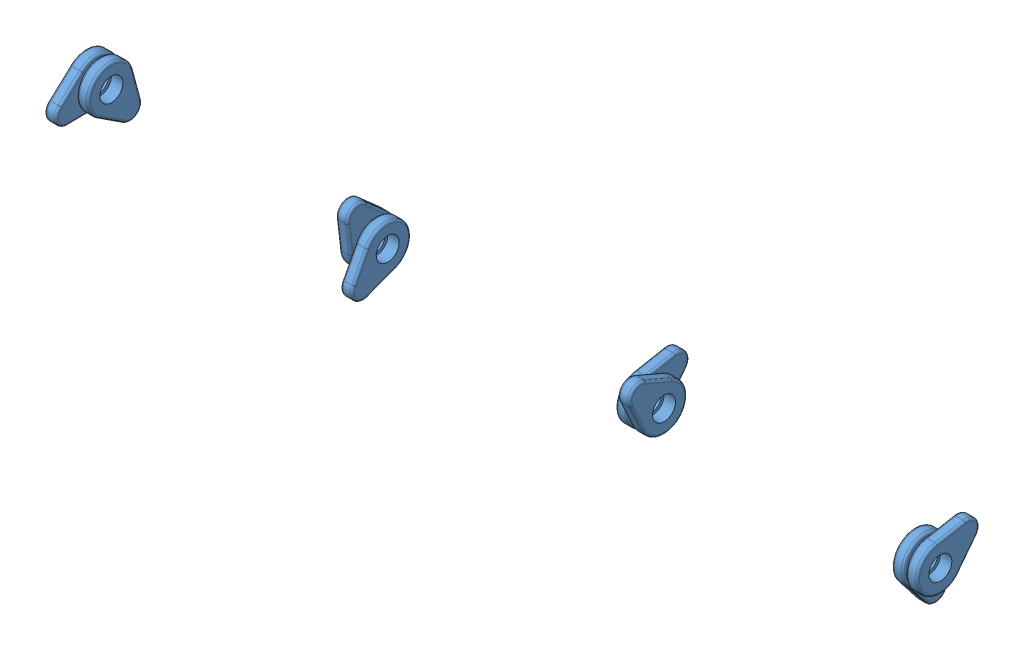
SolidWorks assembly CamRail, configuration Default. Lengths in mm.
Overall size (371 49.3 48.3).
4 component instances, 1 part files, 19 mates.
Components (placement in the parent):
- camX2-1: camX2 [Default] at (-44.0304 461.1901 -302.0136) x (1 0 0) z (0 0.370458 -0.928849) size (11 28.57 29)
- camX2-2: camX2 [Default] at (195.9696 455.2948 -361.5788) x (1 0 0) z (0 -0.52378 0.851854) size (11 28.57 29)
- camX2-7: camX2 [Default] at (75.9696 485.6121 -334.0504) x (1 0 0) z (0 -0.886785 -0.462182) size (11 28.57 29)
- camX2-8: camX2 [Default] at (315.9696 426.6801 -323.7036) x (1 0 0) z (0 0.955327 0.295551) size (11 28.57 29)
Mates (geometry in assembly coordinates):
- Concentric23: concentric aligned: circle of ?; circle of camX2-8
- Concentric24: concentric aligned: circle of ?; circle of camX2-8
- Concentric25: concentric aligned: circle of camX2-1; circle of ?
- Concentric26: concentric aligned: circle of camX2-1; circle of ?
- Concentric27: concentric aligned: circle of ?; circle of camX2-7
- Concentric29: concentric aligned: circle of ?; circle of camX2-7
- Concentric30: concentric aligned: circle of camX2-2; circle of ?
- Concentric31: concentric aligned: circle of camX2-2; circle of ?
- Concentric32: concentric anti-aligned: cylinder of camX2-1 through (-29.2926 455.6781 -331.5424) axis (-1 0 0) radius 5; circle of ?
- Concentric33: concentric aligned: cylinder of camX2-1 through (-29.2926 455.6781 -331.5424) axis (-1 0 0) radius 5; cylinder of ? through (117.7074 455.6781 -331.5424) axis (-1 0 0) radius 5
- Concentric34: concentric anti-aligned: cylinder of camX2-2 through (210.7074 455.6781 -331.5424) axis (-1 0 0) radius 5; circle of ?
- Concentric35: concentric anti-aligned: cylinder of camX2-2 through (210.7074 455.6781 -331.5424) axis (-1 0 0) radius 5; circle of camX2-8
- Distance1: distance = 95 mm anti-aligned: plane of camX2-1 through (-34.2926 455.6781 -331.5424) normal (-1 0 0); plane of ? through (-129.2926 455.6781 -331.5424) normal (1 0 0)
- Distance2: distance = 16 mm anti-aligned: plane of ? through (-7.2926 455.6781 -331.5424) normal (-1 0 0); plane of camX2-1 through (-23.2926 455.6781 -331.5424) normal (1 0 0)
- Distance3: distance = 82 mm anti-aligned: plane of ? through (3.7074 455.6781 -331.5424) normal (1 0 0); plane of camX2-7 through (85.7074 455.6781 -331.5424) normal (-1 0 0)
- Distance4: distance = 16 mm anti-aligned: plane of camX2-7 through (96.7074 455.6781 -331.5424) normal (1 0 0); plane of ? through (112.7074 455.6781 -331.5424) normal (-1 0 0)
- Distance5: distance = 82 mm anti-aligned: plane of camX2-2 through (205.7074 455.6781 -331.5424) normal (-1 0 0); plane of ? through (123.7074 455.6781 -331.5424) normal (1 0 0)
- Distance6: distance = 16 mm anti-aligned: plane of ? through (232.7074 455.6781 -331.5424) normal (-1 0 0); plane of camX2-2 through (216.7074 455.6781 -331.5424) normal (1 0 0)
- Distance7: distance = 82 mm anti-aligned: plane of camX2-8 through (325.7074 455.6781 -331.5424) normal (-1 0 0); plane of ? through (243.7074 455.6781 -331.5424) normal (1 0 0)
